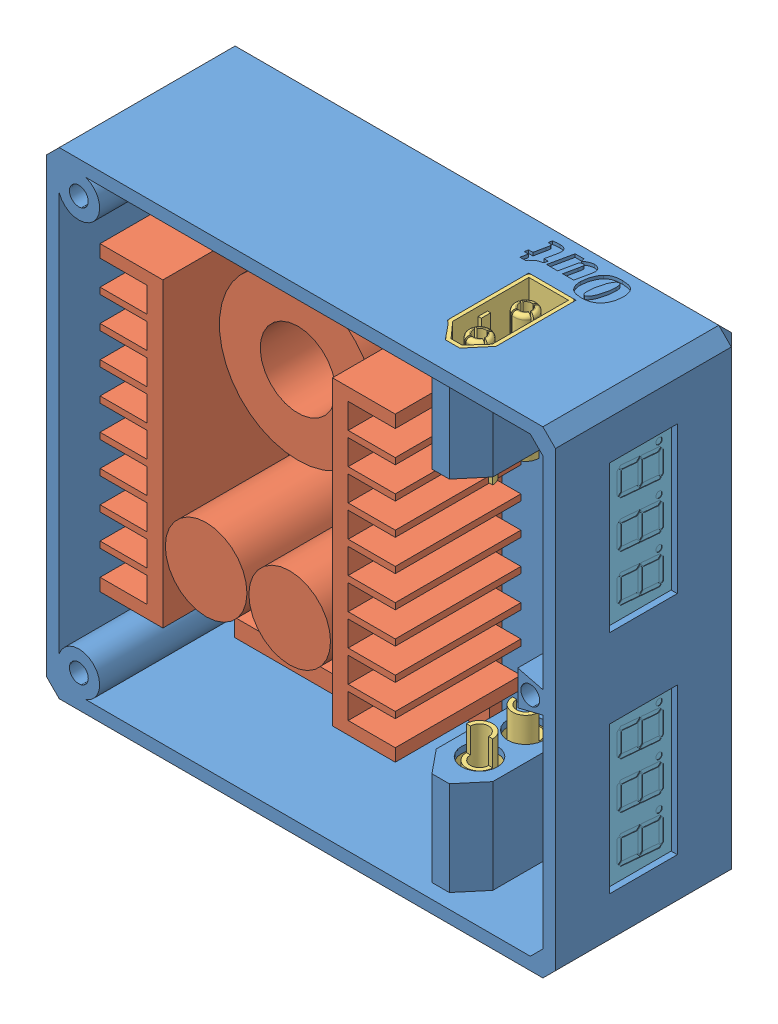
SolidWorks assembly Assembly Cover Power Up, configuration Default. Lengths in mm.
Overall size (81 76 30).
219 component instances, 110 part files, 17 mates.
Components (placement in the parent):
- Base-1: Base [Default] at (8.8914 39.7729 49.4428) size (81 76 30)
- Step-Up Module-1: Step-Up Module [Default] at (-6.1086 39.7729 53.4428) x (0 -1 0) z (0 0 1) size (65 47 22)
- XT60FemaleConnector-1: XT60FemaleConnector [Default] at (26.3235 9.7729 65.8371) x (0 1 0) z (0 0 -1) size (20.5 7.5 16.55)
- Seven Segment-1: Seven Segment [Default] at (46.3914 21.8579 65.4428) x (0 1 0) z (1 0 0) size (30.5 10.59 12.1)
  - Seven Segment1-1: Seven Segment1 [Default] at origin size (22.61 10.1 5.41)
  - Seven Segment2-1: Seven Segment2 [Default] at origin size (22.6 10 0.1)
  - Seven Segment3-1: Seven Segment3 [Default] at origin size (21.6 9 0.8)
  - Seven Segment4-1: Seven Segment4 [Default] at origin size (0.6 0.6 5.4)
  - Seven Segment5-1: Seven Segment5 [Default] at origin size (0.6 0.6 5.4)
  - Seven Segment6-1: Seven Segment6 [Default] at origin size (0.6 0.6 5.4)
  - Seven Segment7-1: Seven Segment7 [Default] at origin size (0.6 0.6 5.4)
  - Seven Segment8-1: Seven Segment8 [Default] at origin size (0.6 0.6 5.4)
  - Seven Segment9-1: Seven Segment9 [Default] at origin size (0.6 0.6 5.4)
  - Seven Segment10-1: Seven Segment10 [Default] at origin size (0.6 0.6 5.4)
  - Seven Segment11-1: Seven Segment11 [Default] at origin size (0.6 0.6 5.4)
  - Seven Segment12-1: Seven Segment12 [Default] at origin size (0.6 0.6 5.4)
  - Seven Segment13-1: Seven Segment13 [Default] at origin size (0.6 0.6 5.4)
  - Seven Segment14-1: Seven Segment14 [Default] at origin size (0.6 0.6 5.4)
  - Seven Segment15-1: Seven Segment15 [Default] at origin size (30.5 10.5 1.5)
  - Seven Segment16-1: Seven Segment16 [Default] at origin size (0.8 0.8 0.02)
  - Seven Segment17-1: Seven Segment17 [Default] at origin size (0.8 0.8 0.02)
  - Seven Segment18-1: Seven Segment18 [Default] at origin size (1.3 1.3 0.02)
  - Seven Segment19-1: Seven Segment19 [Default] at origin size (1 1 1.54)
  - Seven Segment20-1: Seven Segment20 [Default] at origin size (1 1 1.54)
  - Seven Segment21-1: Seven Segment21 [Default] at origin size (1 1 1.54)
  - Seven Segment22-1: Seven Segment22 [Default] at origin size (1.3 1.3 0.02)
  - Seven Segment23-1: Seven Segment23 [Default] at origin size (1.3 1.3 0.02)
  - Seven Segment24-1: Seven Segment24 [Default] at origin size (1.3 1.3 0.02)
  - Seven Segment25-1: Seven Segment25 [Default] at origin size (1.3 1.3 0.02)
  - Seven Segment26-1: Seven Segment26 [Default] at origin size (1.3 1.3 0.02)
  - Seven Segment27-1: Seven Segment27 [Default] at origin size (1.3 1.3 0.02)
  - Seven Segment28-1: Seven Segment28 [Default] at origin size (1.3 1.3 0.02)
  - Seven Segment29-1: Seven Segment29 [Default] at origin size (1.3 1.3 0.02)
  - Seven Segment30-1: Seven Segment30 [Default] at origin size (1.3 1.3 0.02)
  - Seven Segment31-1: Seven Segment31 [Default] at origin size (1.3 1.3 0.02)
  - Seven Segment32-1: Seven Segment32 [Default] at origin size (8.8 6.1 1.6)
  - Seven Segment33-1: Seven Segment33 [Default] at origin size (0.97 1 0.37)
  - Seven Segment34-1: Seven Segment34 [Default] at origin size (0.97 1.01 0.37)
  - Seven Segment35-1: Seven Segment35 [Default] at origin size (0.97 1 0.37)
  - Seven Segment36-1: Seven Segment36 [Default] at origin size (0.97 1.01 0.37)
  - Seven Segment37-1: Seven Segment37 [Default] at origin size (0.97 1 0.37)
  - Seven Segment38-1: Seven Segment38 [Default] at origin size (0.97 1.01 0.37)
  - Seven Segment39-1: Seven Segment39 [Default] at origin size (0.97 1 0.37)
  - Seven Segment40-1: Seven Segment40 [Default] at origin size (0.97 1.01 0.37)
  - Seven Segment41-1: Seven Segment41 [Default] at origin size (0.97 1 0.37)
  - Seven Segment42-1: Seven Segment42 [Default] at origin size (0.97 1.01 0.37)
  - Seven Segment43-1: Seven Segment43 [Default] at origin size (0.97 1 0.37)
  - Seven Segment44-1: Seven Segment44 [Default] at origin size (0.97 1.01 0.37)
  - Seven Segment45-1: Seven Segment45 [Default] at origin size (0.97 1 0.37)
  - Seven Segment46-1: Seven Segment46 [Default] at origin size (0.97 1.01 0.37)
  - Seven Segment47-1: Seven Segment47 [Default] at origin size (4.5 2.5 1.55)
  - Seven Segment48-1: Seven Segment48 [Default] at origin size (1.6 4 0.4)
  - Seven Segment49-1: Seven Segment49 [Default] at origin size (0.42 1.13 0.4)
  - Seven Segment50-1: Seven Segment50 [Default] at origin size (0.42 1.13 0.4)
  - Seven Segment51-1: Seven Segment51 [Default] at origin size (1.81 1.11 0.31)
  - Seven Segment52-1: Seven Segment52 [Default] at origin size (0.81 1.21 0.31)
  - Seven Segment53-1: Seven Segment53 [Default] at origin size (0.81 1.21 0.31)
  - Seven Segment54-1: Seven Segment54 [Default] at origin size (0.81 1.21 0.31)
  - Seven Segment55-1: Seven Segment55 [Default] at origin size (1.3 1.3 0.9)
  - Seven Segment56-1: Seven Segment56 [Default] at origin size (1.3 1.3 0.9)
  - Seven Segment57-1: Seven Segment57 [Default] at origin size (1.3 1.3 0.9)
  - Seven Segment58-1: Seven Segment58 [Default] at origin size (1.3 1.3 0.9)
  - Seven Segment59-1: Seven Segment59 [Default] at origin size (1.3 1.3 0.9)
  - Seven Segment60-1: Seven Segment60 [Default] at origin size (1.3 1.3 0.9)
  - Seven Segment61-1: Seven Segment61 [Default] at origin size (1.3 1.3 0.9)
  - Seven Segment62-1: Seven Segment62 [Default] at origin size (1.3 1.3 0.9)
  - Seven Segment63-1: Seven Segment63 [Default] at origin size (1.3 1.3 0.9)
  - Seven Segment64-1: Seven Segment64 [Default] at origin size (1.3 1.3 0.9)
  - Seven Segment65-1: Seven Segment65 [Default] at origin size (1.3 1.3 0.9)
  - Seven Segment66-1: Seven Segment66 [Default] at origin size (3.1 3.25 0.5)
  - Seven Segment67-1: Seven Segment67 [Default] at origin size (1.4 2.55 1.25)
  - Seven Segment68-1: Seven Segment68 [Default] at origin size (0.6 0.65 0.85)
  - Seven Segment69-1: Seven Segment69 [Default] at origin size (0.6 0.65 0.85)
  - Seven Segment70-1: Seven Segment70 [Default] at origin size (2.8 3 0.05)
  - Seven Segment71-1: Seven Segment71 [Default] at origin size (3.11 3.11 0.95)
  - Seven Segment72-1: Seven Segment72 [Default] at origin size (1.31 2.56 0.17)
  - Seven Segment73-1: Seven Segment73 [Default] at origin size (1.01 1.01 0.17)
  - Seven Segment74-1: Seven Segment74 [Default] at origin size (1.01 1.01 0.17)
  - Seven Segment75-1: Seven Segment75 [Default] at origin size (1.8 1.35 0.8)
  - Seven Segment76-1: Seven Segment76 [Default] at origin size (0.55 0.4 0.6)
  - Seven Segment77-1: Seven Segment77 [Default] at origin size (0.55 0.4 0.6)
  - Seven Segment78-1: Seven Segment78 [Default] at origin size (0.9 1 0.3)
  - Seven Segment79-1: Seven Segment79 [Default] at origin size (0.9 1 0.3)
  - Seven Segment80-1: Seven Segment80 [Default] at origin size (1.1 2 0.85)
  - Seven Segment81-1: Seven Segment81 [Default] at origin size (0.94 0.32 0.4)
  - Seven Segment82-1: Seven Segment82 [Default] at origin size (0.94 0.32 0.4)
  - Seven Segment83-1: Seven Segment83 [Default] at origin size (2 1.1 0.85)
  - Seven Segment84-1: Seven Segment84 [Default] at origin size (0.32 1.04 0.4)
  - Seven Segment85-1: Seven Segment85 [Default] at origin size (0.32 1.04 0.4)
  - Seven Segment86-1: Seven Segment86 [Default] at origin size (1.8 0.8 0.65)
  - Seven Segment87-1: Seven Segment87 [Default] at origin size (0.32 0.74 0.4)
  - Seven Segment88-1: Seven Segment88 [Default] at origin size (0.32 0.74 0.4)
  - Seven Segment89-1: Seven Segment89 [Default] at origin size (1.6 0.8 0.45)
  - Seven Segment90-1: Seven Segment90 [Default] at origin size (0.3 0.75 0.3)
  - Seven Segment91-1: Seven Segment91 [Default] at origin size (0.3 0.75 0.3)
  - Seven Segment92-1: Seven Segment92 [Default] at origin size (1.6 0.8 0.45)
  - Seven Segment93-1: Seven Segment93 [Default] at origin size (0.3 0.75 0.3)
  - Seven Segment94-1: Seven Segment94 [Default] at origin size (0.3 0.75 0.3)
  - Seven Segment95-1: Seven Segment95 [Default] at origin size (1.6 0.8 0.45)
  - Seven Segment96-1: Seven Segment96 [Default] at origin size (0.3 0.75 0.3)
  - Seven Segment97-1: Seven Segment97 [Default] at origin size (0.3 0.75 0.3)
  - Seven Segment98-1: Seven Segment98 [Default] at origin size (0.4 1.16 6.08)
  - Seven Segment99-1: Seven Segment99 [Default] at origin size (1.28 1.78 3.82)
  - Seven Segment100-1: Seven Segment100 [Default] at origin size (0.4 1.16 6.08)
  - Seven Segment101-1: Seven Segment101 [Default] at origin size (1.28 1.78 3.82)
  - Seven Segment102-1: Seven Segment102 [Default] at origin size (0.4 1.16 6.08)
  - Seven Segment103-1: Seven Segment103 [Default] at origin size (1.28 1.78 3.82)
  - Seven Segment104-1: Seven Segment104 [Default] at origin size (1.2 1.2 0.51)
  - Seven Segment105-1: Seven Segment105 [Default] at origin size (1.2 1.2 0.51)
  - Seven Segment106-1: Seven Segment106 [Default] at origin size (1.2 1.2 0.51)
- Seven Segment-3: Seven Segment [Default] at (46.3914 57.8579 65.4428) x (0 1 0) z (1 0 0) size (30.5 10.59 12.1)
  - Seven Segment1-1: Seven Segment1 [Default] at origin size (22.61 10.1 5.41)
  - Seven Segment2-1: Seven Segment2 [Default] at origin size (22.6 10 0.1)
  - Seven Segment3-1: Seven Segment3 [Default] at origin size (21.6 9 0.8)
  - Seven Segment4-1: Seven Segment4 [Default] at origin size (0.6 0.6 5.4)
  - Seven Segment5-1: Seven Segment5 [Default] at origin size (0.6 0.6 5.4)
  - Seven Segment6-1: Seven Segment6 [Default] at origin size (0.6 0.6 5.4)
  - Seven Segment7-1: Seven Segment7 [Default] at origin size (0.6 0.6 5.4)
  - Seven Segment8-1: Seven Segment8 [Default] at origin size (0.6 0.6 5.4)
  - Seven Segment9-1: Seven Segment9 [Default] at origin size (0.6 0.6 5.4)
  - Seven Segment10-1: Seven Segment10 [Default] at origin size (0.6 0.6 5.4)
  - Seven Segment11-1: Seven Segment11 [Default] at origin size (0.6 0.6 5.4)
  - Seven Segment12-1: Seven Segment12 [Default] at origin size (0.6 0.6 5.4)
  - Seven Segment13-1: Seven Segment13 [Default] at origin size (0.6 0.6 5.4)
  - Seven Segment14-1: Seven Segment14 [Default] at origin size (0.6 0.6 5.4)
  - Seven Segment15-1: Seven Segment15 [Default] at origin size (30.5 10.5 1.5)
  - Seven Segment16-1: Seven Segment16 [Default] at origin size (0.8 0.8 0.02)
  - Seven Segment17-1: Seven Segment17 [Default] at origin size (0.8 0.8 0.02)
  - Seven Segment18-1: Seven Segment18 [Default] at origin size (1.3 1.3 0.02)
  - Seven Segment19-1: Seven Segment19 [Default] at origin size (1 1 1.54)
  - Seven Segment20-1: Seven Segment20 [Default] at origin size (1 1 1.54)
  - Seven Segment21-1: Seven Segment21 [Default] at origin size (1 1 1.54)
  - Seven Segment22-1: Seven Segment22 [Default] at origin size (1.3 1.3 0.02)
  - Seven Segment23-1: Seven Segment23 [Default] at origin size (1.3 1.3 0.02)
  - Seven Segment24-1: Seven Segment24 [Default] at origin size (1.3 1.3 0.02)
  - Seven Segment25-1: Seven Segment25 [Default] at origin size (1.3 1.3 0.02)
  - Seven Segment26-1: Seven Segment26 [Default] at origin size (1.3 1.3 0.02)
  - Seven Segment27-1: Seven Segment27 [Default] at origin size (1.3 1.3 0.02)
  - Seven Segment28-1: Seven Segment28 [Default] at origin size (1.3 1.3 0.02)
  - Seven Segment29-1: Seven Segment29 [Default] at origin size (1.3 1.3 0.02)
  - Seven Segment30-1: Seven Segment30 [Default] at origin size (1.3 1.3 0.02)
  - Seven Segment31-1: Seven Segment31 [Default] at origin size (1.3 1.3 0.02)
  - Seven Segment32-1: Seven Segment32 [Default] at origin size (8.8 6.1 1.6)
  - Seven Segment33-1: Seven Segment33 [Default] at origin size (0.97 1 0.37)
  - Seven Segment34-1: Seven Segment34 [Default] at origin size (0.97 1.01 0.37)
  - Seven Segment35-1: Seven Segment35 [Default] at origin size (0.97 1 0.37)
  - Seven Segment36-1: Seven Segment36 [Default] at origin size (0.97 1.01 0.37)
  - Seven Segment37-1: Seven Segment37 [Default] at origin size (0.97 1 0.37)
  - Seven Segment38-1: Seven Segment38 [Default] at origin size (0.97 1.01 0.37)
  - Seven Segment39-1: Seven Segment39 [Default] at origin size (0.97 1 0.37)
  - Seven Segment40-1: Seven Segment40 [Default] at origin size (0.97 1.01 0.37)
  - Seven Segment41-1: Seven Segment41 [Default] at origin size (0.97 1 0.37)
  - Seven Segment42-1: Seven Segment42 [Default] at origin size (0.97 1.01 0.37)
  - Seven Segment43-1: Seven Segment43 [Default] at origin size (0.97 1 0.37)
  - Seven Segment44-1: Seven Segment44 [Default] at origin size (0.97 1.01 0.37)
  - Seven Segment45-1: Seven Segment45 [Default] at origin size (0.97 1 0.37)
  - Seven Segment46-1: Seven Segment46 [Default] at origin size (0.97 1.01 0.37)
  - Seven Segment47-1: Seven Segment47 [Default] at origin size (4.5 2.5 1.55)
  - Seven Segment48-1: Seven Segment48 [Default] at origin size (1.6 4 0.4)
  - Seven Segment49-1: Seven Segment49 [Default] at origin size (0.42 1.13 0.4)
  - Seven Segment50-1: Seven Segment50 [Default] at origin size (0.42 1.13 0.4)
  - Seven Segment51-1: Seven Segment51 [Default] at origin size (1.81 1.11 0.31)
  - Seven Segment52-1: Seven Segment52 [Default] at origin size (0.81 1.21 0.31)
  - Seven Segment53-1: Seven Segment53 [Default] at origin size (0.81 1.21 0.31)
  - Seven Segment54-1: Seven Segment54 [Default] at origin size (0.81 1.21 0.31)
  - Seven Segment55-1: Seven Segment55 [Default] at origin size (1.3 1.3 0.9)
  - Seven Segment56-1: Seven Segment56 [Default] at origin size (1.3 1.3 0.9)
  - Seven Segment57-1: Seven Segment57 [Default] at origin size (1.3 1.3 0.9)
  - Seven Segment58-1: Seven Segment58 [Default] at origin size (1.3 1.3 0.9)
  - Seven Segment59-1: Seven Segment59 [Default] at origin size (1.3 1.3 0.9)
  - Seven Segment60-1: Seven Segment60 [Default] at origin size (1.3 1.3 0.9)
  - Seven Segment61-1: Seven Segment61 [Default] at origin size (1.3 1.3 0.9)
  - Seven Segment62-1: Seven Segment62 [Default] at origin size (1.3 1.3 0.9)
  - Seven Segment63-1: Seven Segment63 [Default] at origin size (1.3 1.3 0.9)
  - Seven Segment64-1: Seven Segment64 [Default] at origin size (1.3 1.3 0.9)
  - Seven Segment65-1: Seven Segment65 [Default] at origin size (1.3 1.3 0.9)
  - Seven Segment66-1: Seven Segment66 [Default] at origin size (3.1 3.25 0.5)
  - Seven Segment67-1: Seven Segment67 [Default] at origin size (1.4 2.55 1.25)
  - Seven Segment68-1: Seven Segment68 [Default] at origin size (0.6 0.65 0.85)
  - Seven Segment69-1: Seven Segment69 [Default] at origin size (0.6 0.65 0.85)
  - Seven Segment70-1: Seven Segment70 [Default] at origin size (2.8 3 0.05)
  - Seven Segment71-1: Seven Segment71 [Default] at origin size (3.11 3.11 0.95)
  - Seven Segment72-1: Seven Segment72 [Default] at origin size (1.31 2.56 0.17)
  - Seven Segment73-1: Seven Segment73 [Default] at origin size (1.01 1.01 0.17)
  - Seven Segment74-1: Seven Segment74 [Default] at origin size (1.01 1.01 0.17)
  - Seven Segment75-1: Seven Segment75 [Default] at origin size (1.8 1.35 0.8)
  - Seven Segment76-1: Seven Segment76 [Default] at origin size (0.55 0.4 0.6)
  - Seven Segment77-1: Seven Segment77 [Default] at origin size (0.55 0.4 0.6)
  - Seven Segment78-1: Seven Segment78 [Default] at origin size (0.9 1 0.3)
  - Seven Segment79-1: Seven Segment79 [Default] at origin size (0.9 1 0.3)
  - Seven Segment80-1: Seven Segment80 [Default] at origin size (1.1 2 0.85)
  - Seven Segment81-1: Seven Segment81 [Default] at origin size (0.94 0.32 0.4)
  - Seven Segment82-1: Seven Segment82 [Default] at origin size (0.94 0.32 0.4)
  - Seven Segment83-1: Seven Segment83 [Default] at origin size (2 1.1 0.85)
  - Seven Segment84-1: Seven Segment84 [Default] at origin size (0.32 1.04 0.4)
  - Seven Segment85-1: Seven Segment85 [Default] at origin size (0.32 1.04 0.4)
  - Seven Segment86-1: Seven Segment86 [Default] at origin size (1.8 0.8 0.65)
  - Seven Segment87-1: Seven Segment87 [Default] at origin size (0.32 0.74 0.4)
  - Seven Segment88-1: Seven Segment88 [Default] at origin size (0.32 0.74 0.4)
  - Seven Segment89-1: Seven Segment89 [Default] at origin size (1.6 0.8 0.45)
  - Seven Segment90-1: Seven Segment90 [Default] at origin size (0.3 0.75 0.3)
  - Seven Segment91-1: Seven Segment91 [Default] at origin size (0.3 0.75 0.3)
  - Seven Segment92-1: Seven Segment92 [Default] at origin size (1.6 0.8 0.45)
  - Seven Segment93-1: Seven Segment93 [Default] at origin size (0.3 0.75 0.3)
  - Seven Segment94-1: Seven Segment94 [Default] at origin size (0.3 0.75 0.3)
  - Seven Segment95-1: Seven Segment95 [Default] at origin size (1.6 0.8 0.45)
  - Seven Segment96-1: Seven Segment96 [Default] at origin size (0.3 0.75 0.3)
  - Seven Segment97-1: Seven Segment97 [Default] at origin size (0.3 0.75 0.3)
  - Seven Segment98-1: Seven Segment98 [Default] at origin size (0.4 1.16 6.08)
  - Seven Segment99-1: Seven Segment99 [Default] at origin size (1.28 1.78 3.82)
  - Seven Segment100-1: Seven Segment100 [Default] at origin size (0.4 1.16 6.08)
  - Seven Segment101-1: Seven Segment101 [Default] at origin size (1.28 1.78 3.82)
  - Seven Segment102-1: Seven Segment102 [Default] at origin size (0.4 1.16 6.08)
  - Seven Segment103-1: Seven Segment103 [Default] at origin size (1.28 1.78 3.82)
  - Seven Segment104-1: Seven Segment104 [Default] at origin size (1.2 1.2 0.51)
  - Seven Segment105-1: Seven Segment105 [Default] at origin size (1.2 1.2 0.51)
  - Seven Segment106-1: Seven Segment106 [Default] at origin size (1.2 1.2 0.51)
- XT60FemaleConnector-2: XT60FemaleConnector [Default] at (26.3235 69.7729 65.8371) x (0 -1 0) z (0 0 -1) size (20.5 7.5 16.55)
- Lid-1: Lid [Default] at (8.8914 39.7729 79.4428) size (81 76 7) (hidden)
Mates (geometry in assembly coordinates):
- Concentric1: concentric anti-aligned: cylinder of Base-1 through (-19.1086 68.7729 51.4428) axis (0 0 -1) radius 1.25; cylinder of Step-Up Module-1 through (-19.1086 68.7729 53.4428) axis (0 0 1) radius 1.5
- Concentric2: concentric anti-aligned: cylinder of Base-1 through (6.8914 68.7729 51.4428) axis (0 0 -1) radius 1.25; cylinder of Step-Up Module-1 through (6.8914 68.7729 53.4428) axis (0 0 1) radius 1.5
- Coincident1: coincident anti-aligned: plane of Base-1 through (6.8914 68.7729 53.4428) normal (0 0 1); plane of Step-Up Module-1 through (-24.6186 7.2629 53.4428) normal (0 0 -1)
- Coincident3: coincident aligned: plane of Base-1 through (8.8914 1.7729 79.4428) normal (0 -1 0); plane of XT60FemaleConnector-1 through (26.3235 1.7729 65.8371) normal (0 -1 0)
- Coincident4: coincident anti-aligned: plane of Base-1 through (22.5735 21.3078 72.0821) normal (1 0 0); plane of XT60FemaleConnector-1 through (22.5735 17.7729 72.3121) normal (-1 0 0)
- Coincident5: coincident anti-aligned: plane of Base-1 through (30.0735 21.3078 59.3621) normal (0 0 1); plane of XT60FemaleConnector-1 through (22.5735 17.7729 59.3621) normal (0 0 -1)
- Concentric6: concentric: cylinder of Base-1 through (40.8914 35.1079 65.4428) axis (1 0 0) radius 1.25; cylinder of Seven Segment-1/Seven Segment15-1 through (38.8914 35.1079 65.4428) axis (-1 0 0) radius 1.05
- Concentric8: concentric anti-aligned: cylinder of Base-1 through (40.8914 71.1079 65.4428) axis (1 0 0) radius 1.25; cylinder of Seven Segment-3/Seven Segment15-1 through (40.8914 71.1079 65.4428) axis (-1 0 0) radius 1.05
- Parallel2: parallel anti-aligned: plane of Base-1 through (19.1194 46.0729 70.8428) normal (0 0 -1); plane of Seven Segment-3/Seven Segment1-1 through (46.2924 46.5569 70.4428) normal (0 0 1)
- Coincident6: coincident anti-aligned: plane of Base-1 through (40.8914 39.7729 49.4428) normal (-1 0 0); plane of Seven Segment-3/Seven Segment15-1 through (40.8914 73.1089 70.6938) normal (1 0 0)
- Concentric10: concentric aligned: cylinder of Base-1 through (26.3235 60.7729 70.9621) axis (0 1 0) radius 2.85; cylinder of XT60FemaleConnector-2 through (26.3235 57.2729 70.9621) axis (0 1 0) radius 2.1
- Concentric11: concentric aligned: cylinder of Base-1 through (26.3235 60.7729 63.6121) axis (0 1 0) radius 2.85; cylinder of XT60FemaleConnector-2 through (26.3235 57.2729 63.6121) axis (0 1 0) radius 2.1
- Coincident8: coincident anti-aligned: plane of Base-1 through (8.8914 61.7729 49.4428) normal (0 1 0); plane of XT60FemaleConnector-2 through (26.3235 61.7729 65.8371) normal (0 -1 0)
- Coincident9: coincident aligned: plane of Base-1 through (-34.1086 39.7729 79.4428) normal (-1 0 0); plane of Lid-1 through (-34.1086 39.7729 84.4428) normal (-1 0 0)
- Coincident10: coincident aligned: plane of Base-1 through (8.8914 77.7729 79.4428) normal (0 1 0); plane of Lid-1 through (8.8914 77.7729 84.4428) normal (0 1 0)
- Coincident11: coincident anti-aligned: plane of Base-1 through (8.8914 39.7729 79.4428) normal (0 0 1); plane of Lid-1 through (8.8914 39.7729 79.4428) normal (0 0 -1)
- Coincident12: coincident anti-aligned: plane of Base-1 through (40.8914 39.7729 49.4428) normal (-1 0 0); plane of Seven Segment-1/Seven Segment15-1 through (40.8914 37.1089 70.6938) normal (1 0 0)
